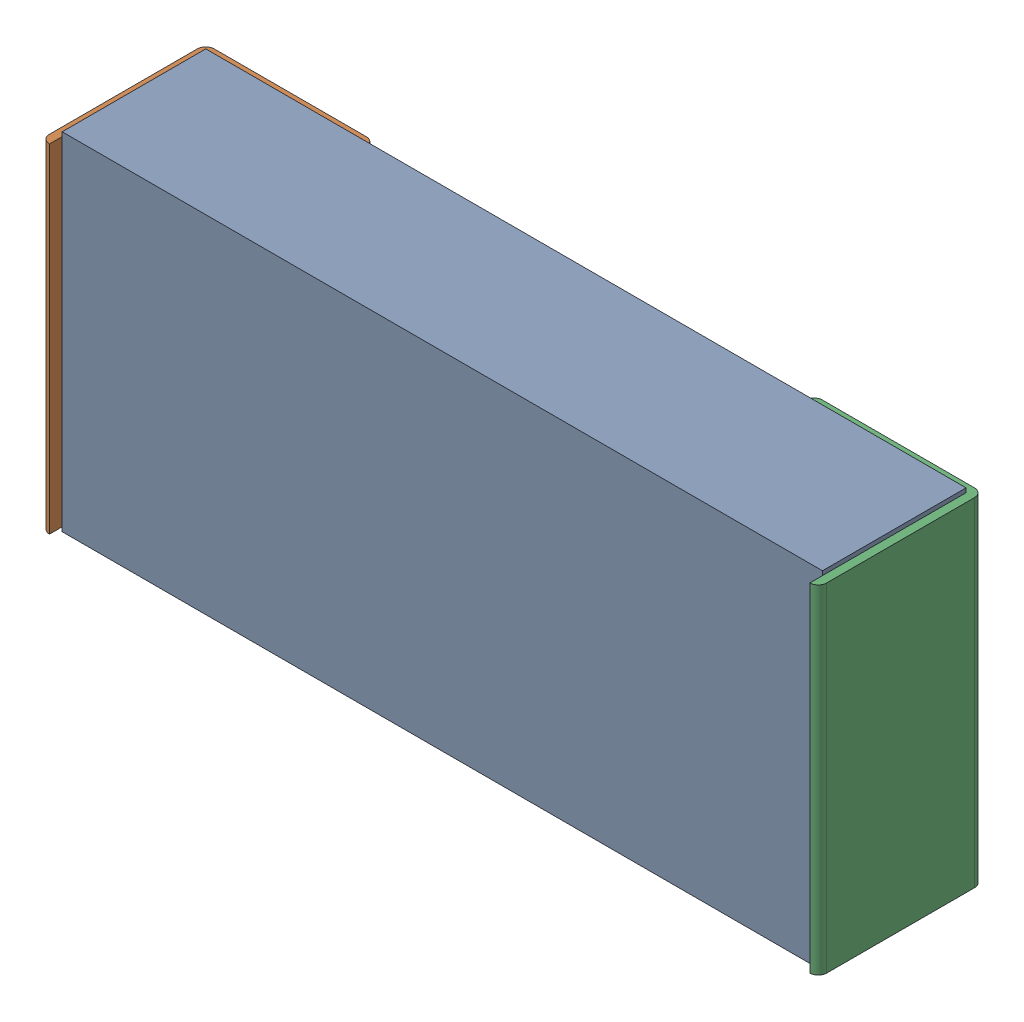
SolidWorks assembly Open CASCADE STEP translator 6.8 1.5.1, configuration Predeterminado. Lengths in mm.
Overall size (2.34 1.04 0.5).
3 component instances, 3 part files, 0 mates.
Components (placement in the parent):
- Body_1_2-1: Body_1_2 [Predeterminado] at origin size (2.29 1.04 0.43)
- Pin_1_2-1: Pin_1_2 [Predeterminado] at (0.3048 0 0) x (-1 0 0) z (0 0 1) size (0.51 1.02 0.5)
- Pin_2_2-1: Pin_2_2 [Predeterminado] at origin size (0.51 1.02 0.5)
